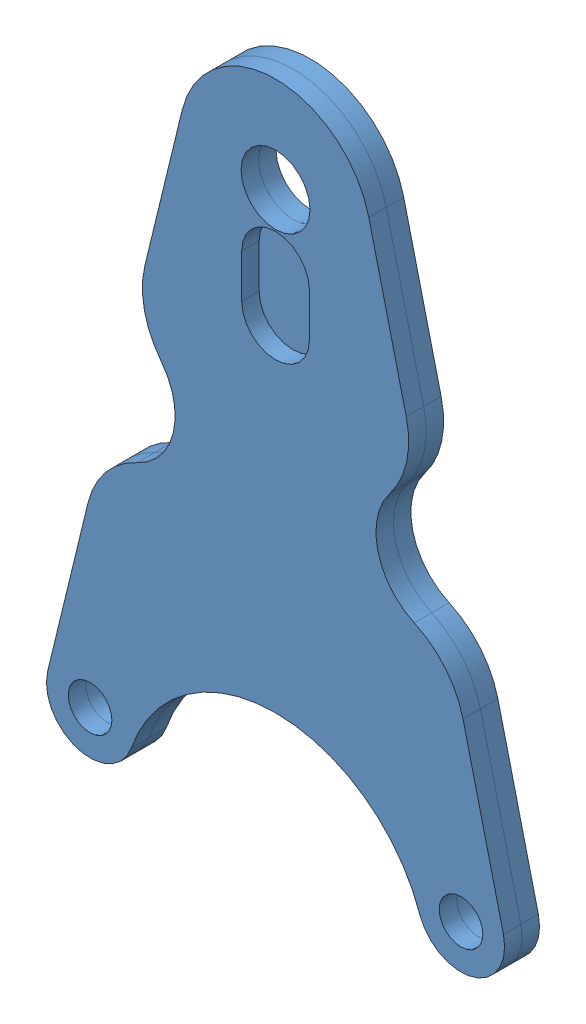
SolidWorks assembly ТП.002.05.03.00 - Качалка управляющая, configuration 00. Lengths in mm.
Overall size (105 156 12).
2 component instances, 1 part files, 3 mates.
Components (placement in the parent):
- ТП.002.05.01.01 - Качалка управляющая-1: ТП.002.05.01.01 - Качалка управляющая [Глухая] at origin size (105 156 12)
- ТП.002.05.01.01 - Качалка управляющая-2: ТП.002.05.01.01 - Качалка управляющая [С вырезом] at origin size (105 156 12)
Mates (geometry in assembly coordinates):
- Концентричный1: concentric: cylinder of ТП.002.05.01.01 - Качалка управляющая-1 through (0 34.3 4) axis (0 0 1) radius 7.9; cylinder of ТП.002.05.01.01 - Качалка управляющая-2 through (0 34.3 12) axis (0 0 -1) radius 7.9
- Совпадение1: coincident: plane of ТП.002.05.01.01 - Качалка управляющая-1 through (42.5 -89.7 8) normal (0 0 1); plane of ТП.002.05.01.01 - Качалка управляющая-2 through (0 -104.4902 8) normal (0 0 -1)
- Концентричный2: concentric: cylinder of ТП.002.05.01.01 - Качалка управляющая-1 through (42.5 -89.7 4) axis (0 0 1) radius 5; cylinder of ТП.002.05.01.01 - Качалка управляющая-2 through (42.5 -89.7 12) axis (0 0 -1) radius 5
